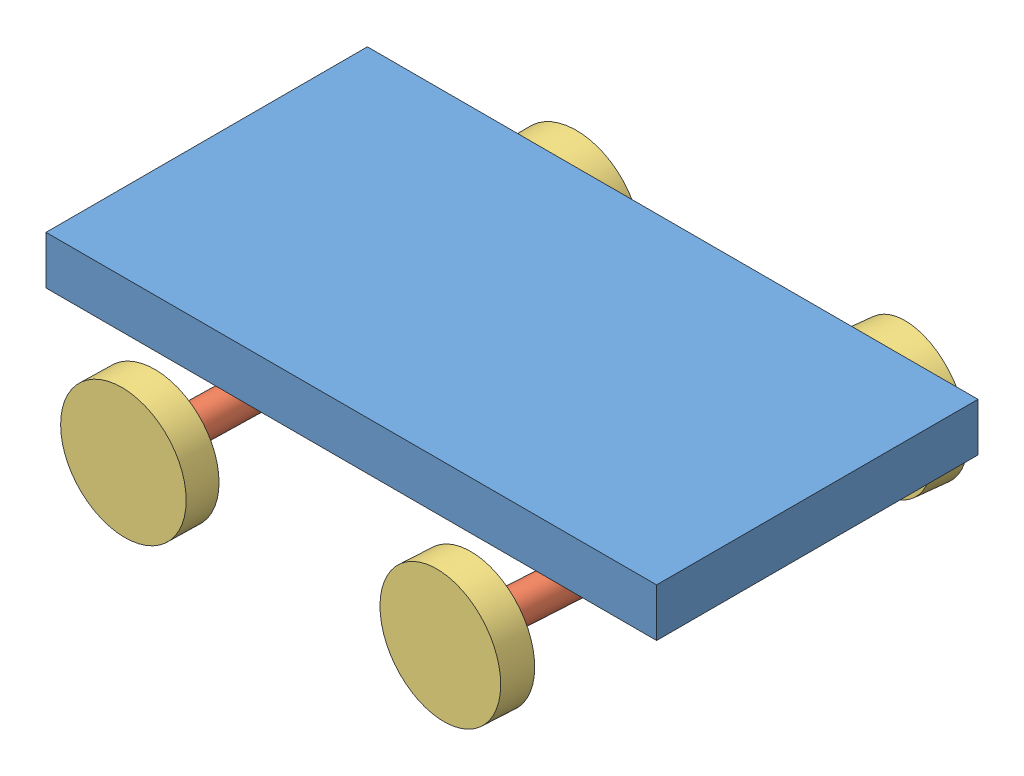
SolidWorks assembly my_robot_1, configuration Default. Lengths in mm.
Overall size (965.2 289.09 729.32).
9 component instances, 3 part files, 16 mates.
Components (placement in the parent):
- chassis-1: chassis [Default] at origin size (965.2 76.2 508)
- steer-1: steer [Default] at (-246.4685 -76.2 149.9548) x (0.023272 0 -0.999729) z (0.999729 0 0.023272) size (177.8 127 50.8)
- steer-2: steer [Default] at (261.5315 -76.2 149.9548) x (0.059265 0 -0.998242) z (0.998242 0 0.059265) size (177.8 127 50.8)
- steer-3: steer [Default] at (-246.4685 -76.2 -154.8452) x (0 0 1) z (-1 0 0) size (177.8 127 50.8)
- steer-4: steer [Default] at (261.5315 -76.2 -154.8452) x (-0.113508 0 0.993537) z (-0.993537 0 -0.113508) size (177.8 127 50.8)
- wheel-1: wheel [Default] at (284.5963 -76.2 -356.732) x (-0.993442 -0.0138 -0.113497) z (-0.013711 0.999905 -0.001566) size (203.2 76.2 203.2)
- wheel-2: wheel [Default] at (-246.4685 -76.2 -358.0452) x (-0.923728 -0.383049 0) z (-0.383049 0.923728 0) size (203.2 76.2 203.2)
- wheel-3: wheel [Default] at (249.4889 -76.2 352.7976) x (-0.889027 -0.454802 -0.052781) z (0.454003 -0.890592 0.026954) size (203.2 76.2 203.2)
- wheel-4: wheel [Default] at (-251.1973 -76.2 353.0997) x (-0.933052 -0.359085 -0.02172) z (0.358988 -0.933305 0.008356) size (203.2 76.2 203.2)
Mates (geometry in assembly coordinates):
- Concentric1: concentric aligned: cylinder of chassis-1 through (-246.4685 25.4 149.9548) axis (0 -1 0) radius 25.4; cylinder of steer-1 through (-246.4685 25.4 149.9548) axis (0 -1 0) radius 25.4
- Coincident1: coincident anti-aligned: plane of chassis-1 through (-246.4685 25.4 149.9548) normal (0 -1 0); plane of steer-1 through (-246.4685 25.4 149.9548) normal (0 1 0)
- Concentric2: concentric aligned: cylinder of chassis-1 through (261.5315 25.4 149.9548) axis (0 -1 0) radius 25.4; cylinder of steer-2 through (261.5315 25.4 149.9548) axis (0 -1 0) radius 25.4
- Coincident2: coincident anti-aligned: plane of chassis-1 through (261.5315 25.4 149.9548) normal (0 -1 0); circle of steer-2
- Concentric4: concentric aligned: cylinder of chassis-1 through (261.5315 25.4 -154.8452) axis (0 -1 0) radius 25.4; cylinder of steer-4 through (261.5315 25.4 -154.8452) axis (0 -1 0) radius 25.4
- Coincident3: coincident anti-aligned: plane of chassis-1 through (261.5315 25.4 -154.8452) normal (0 -1 0); circle of steer-4
- Concentric5: concentric aligned: cylinder of chassis-1 through (-246.4685 25.4 -154.8452) axis (0 -1 0) radius 25.4; cylinder of steer-3 through (-246.4685 25.4 -154.8452) axis (0 -1 0) radius 25.4
- Coincident4: coincident anti-aligned: plane of chassis-1 through (-246.4685 25.4 -154.8452) normal (0 -1 0); circle of steer-3
- Concentric7: concentric aligned: cylinder of steer-4 through (275.947 -76.2 -281.0244) axis (0.113508 0 -0.993537) radius 12.7; cylinder of wheel-1 through (275.947 -76.2 -281.0244) axis (0.113508 0 -0.993537) radius 12.7
- Concentric8: concentric aligned: cylinder of steer-3 through (-246.4685 -76.2 -281.8452) axis (0 0 -1) radius 12.7; cylinder of wheel-2 through (-246.4685 -76.2 -281.8452) axis (0 0 -1) radius 12.7
- Coincident6: coincident anti-aligned: circle of steer-3; circle of wheel-2
- Concentric9: concentric aligned: cylinder of steer-2 through (254.0048 -76.2 276.7315) axis (-0.059265 0 0.998242) radius 12.7; cylinder of wheel-3 through (254.0048 -76.2 276.7315) axis (-0.059265 0 0.998242) radius 12.7
- Coincident7: coincident anti-aligned: plane of steer-2 through (254.0048 -76.2 276.7315) normal (-0.059265 0 0.998242); plane of wheel-3 through (254.0048 -76.2 276.7315) normal (0.059265 0 -0.998242)
- Concentric10: concentric aligned: cylinder of steer-1 through (-249.424 -76.2 276.9204) axis (-0.023272 0 0.999729) radius 12.7; cylinder of wheel-4 through (-249.424 -76.2 276.9204) axis (-0.023272 0 0.999729) radius 12.7
- Coincident8: coincident anti-aligned: circle of steer-1; plane of wheel-4 through (-249.424 -76.2 276.9204) normal (0.023272 0 -0.999729)
- Coincident9: coincident anti-aligned: plane of steer-4 through (275.947 -76.2 -281.0244) normal (0.113508 0 -0.993537); plane of wheel-1 through (275.947 -76.2 -281.0244) normal (-0.113508 0 0.993537)
